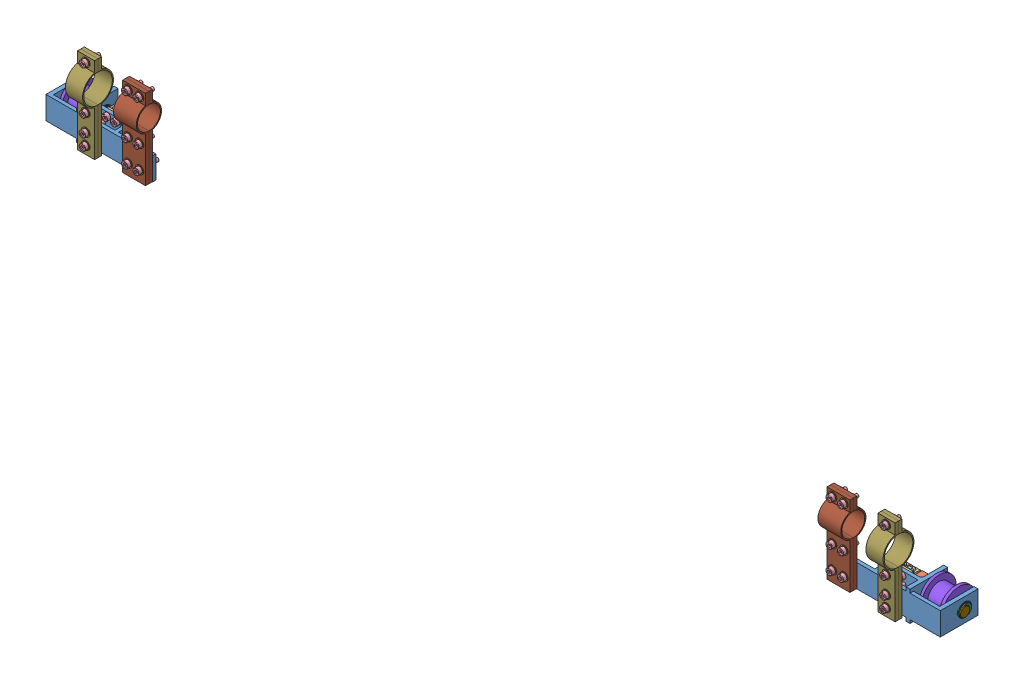
SolidWorks assembly 电机滑轮-安装, configuration 默认. Lengths in mm.
Overall size (785.6 77.7 53).
106 component instances, 12 part files, 64 mates.
Components (placement in the parent):
- 电机安装架-1: 电机安装架 [默认] at (54.9496 2.6319 18.5) size (93 26 33)
- 马达-1: 马达 [默认] at (29.2505 2.4861 -5) x (0 -1 0) z (-1 0 0) size (12 10 36)
- 电机架-1: 电机架 [默认] at (29.2505 2.4861 0) x (0 -1 0.000041) z (-1 0 0) size (25 14.79 18)
- hexagon socket head cap screws gb-2: hexagon socket head cap screws gb [GB_FASTENER_SCREWS_HSHCS M3X10-N] at (23.2502 -7.5147 14) x (0 0 -1) z (1 0 0) size (13 5.5 5.5)
- hexagon socket head cap screws gb-3: hexagon socket head cap screws gb [GB_FASTENER_SCREWS_HSHCS M3X10-N] at (15.2502 -7.5147 14) x (0 0 -1) z (1 0 0) size (13 5.5 5.5)
- hexagon socket head cap screws gb-4: hexagon socket head cap screws gb [GB_FASTENER_SCREWS_HSHCS M3X10-N] at (15.2505 12.4869 14) x (0 0 -1) z (1 0 0) size (13 5.5 5.5)
- hexagon socket head cap screws gb-5: hexagon socket head cap screws gb [GB_FASTENER_SCREWS_HSHCS M3X10-N] at (23.2505 12.4867 14) x (0 0 -1) z (1 0 0) size (13 5.5 5.5)
- hex nuts, style 1-grades ab gb-5: hex nuts, style 1-grades ab gb [GB_FASTENER_NUT_SNAB1 M3-N] at (23.2502 -7.5147 6) size (6.35 5.5 2.4)
- hex nuts, style 1-grades ab gb-7: hex nuts, style 1-grades ab gb [GB_FASTENER_NUT_SNAB1 M3-N] at (15.2502 -7.5147 6) size (6.35 5.5 2.4)
- hex nuts, style 1-grades ab gb-8: hex nuts, style 1-grades ab gb [GB_FASTENER_NUT_SNAB1 M3-N] at (23.2505 12.4867 6) size (6.35 5.5 2.4)
- hex nuts, style 1-grades ab gb-9: hex nuts, style 1-grades ab gb [GB_FASTENER_NUT_SNAB1 M3-N] at (15.2505 12.4869 6) size (6.35 5.5 2.4)
- circlips for shaft--type a small gb-2: circlips for shaft--type a small gb [GB_CONNECTING_PIECE_RING_RRA 8] at (-28.0504 2.432 -0.3255) x (0 -0.986484 0.16386) z (1 0 0) size (9.38 11.87 0.8)
- circlips for shaft--type a small gb-3: circlips for shaft--type a small gb [GB_CONNECTING_PIECE_RING_RRA 8] at (1.9496 2.5402 0.3255) x (0 -0.986484 0.16386) z (-1 0 0) size (9.38 11.87 0.8)
- plain washers-n series-grade a gb-2: plain washers-n series-grade a gb [GB_FASTENER_WASHER_PWNA 3] at (12.9496 -2.5142 28) size (7 7 0.5)
- plain washers-n series-grade a gb-3: plain washers-n series-grade a gb [GB_FASTENER_WASHER_PWNA 3] at (12.9496 7.4858 28) size (7 7 0.5)
- plain washers-n series-grade a gb-4: plain washers-n series-grade a gb [GB_FASTENER_WASHER_PWNA 3] at (59.9496 2.4861 28) size (7 7 0.5)
- plain washers-n series-grade a gb-5: plain washers-n series-grade a gb [GB_FASTENER_WASHER_PWNA 3] at (49.9496 2.4861 28) size (7 7 0.5)
- hexagon socket head cap screws gb-7: hexagon socket head cap screws gb [GB_FASTENER_SCREWS_HSHCS M3X16-N] at (12.9496 -2.5142 31) x (0 0 -1) z (1 0 0) size (19 5.5 5.5)
- hexagon socket head cap screws gb-8: hexagon socket head cap screws gb [GB_FASTENER_SCREWS_HSHCS M3X16-N] at (12.9496 7.4858 31) x (0 0 -1) z (1 0 0) size (19 5.5 5.5)
- hexagon socket head cap screws gb-9: hexagon socket head cap screws gb [GB_FASTENER_SCREWS_HSHCS M3X16-N] at (49.9496 2.4861 31) x (0 0 -1) z (0.99739 -0.072207 0) size (19 5.5 5.5)
- hexagon socket head cap screws gb-10: hexagon socket head cap screws gb [GB_FASTENER_SCREWS_HSHCS M3X16-N] at (59.9496 2.4861 31) x (0 0 -1) z (1 0 0) size (19 5.5 5.5)
- hex nuts, style 1-grades ab gb-11: hex nuts, style 1-grades ab gb [GB_FASTENER_NUT_SNAB1 M3-N] at (59.9496 2.4861 16.1) x (0.923728 0.383049 0) z (0 0 -1) size (6.35 5.5 2.4)
- hex nuts, style 1-grades ab gb-12: hex nuts, style 1-grades ab gb [GB_FASTENER_NUT_SNAB1 M3-N] at (49.9496 2.4861 16.1) x (0.923728 0.383049 0) z (0 0 -1) size (6.35 5.5 2.4)
- hex nuts, style 1-grades ab gb-13: hex nuts, style 1-grades ab gb [GB_FASTENER_NUT_SNAB1 M3-N] at (12.9496 -2.5142 16.1) x (0.923728 0.383049 0) z (0 0 -1) size (6.35 5.5 2.4)
- hex nuts, style 1-grades ab gb-14: hex nuts, style 1-grades ab gb [GB_FASTENER_NUT_SNAB1 M3-N] at (12.9496 7.4858 16.1) x (0.923728 0.383049 0) z (0 0 -1) size (6.35 5.5 2.4)
- 滑轮 - 卷帘-1: 滑轮 - 卷帘 [默认] at (-23.0504 2.4861 0) x (0 0 1) z (0 1 0) size (30 20 30)
- 滑轮轴 - 电机-1: 滑轮轴 - 电机 [默认] at (-13.0504 2.4861 0) x (0 0 -1) z (-1 0 0) size (9.5 9.5 33.6)
- deep groove ball bearings gb-1: deep groove ball bearings gb [Rolling bearings 617-8 GB 276-94] at (0.6996 2.4861 0) size (2.5 12 12)
- deep groove ball bearings gb-2: deep groove ball bearings gb [Rolling bearings 617-8 GB 276-94] at (-26.8004 2.4861 0) size (2.5 12 12)
- 小管夹具-1: 小管夹具 [默认] at (54.9496 11.6833 -31.115) x (0 0 1) z (-1 0 0) size (22 70 20)
  - 夹具-1: 夹具 [默认] at (55.615 31.0944 -10) size (11 70 20)
  - 夹具-2: 夹具 [默认] at (55.615 31.0944 10) x (-1 0 0) z (0 0 -1) size (11 70 20)
  - plain washers-n series-grade a gb-2: plain washers-n series-grade a gb [GB_FASTENER_WASHER_PWNA 3] at (59.115 46.3859 5) x (0 0 -1) z (1 0 0) size (7 7 0.5)
  - plain washers-n series-grade a gb-3: plain washers-n series-grade a gb [GB_FASTENER_WASHER_PWNA 3] at (59.115 46.3859 -5) x (0 0 -1) z (1 0 0) size (7 7 0.5)
  - plain washers-n series-grade a gb-4: plain washers-n series-grade a gb [GB_FASTENER_WASHER_PWNA 3] at (59.115 10.8029 -5) x (0 0 -1) z (1 0 0) size (7 7 0.5)
  - plain washers-n series-grade a gb-5: plain washers-n series-grade a gb [GB_FASTENER_WASHER_PWNA 3] at (59.115 10.8029 5) x (0 0 -1) z (1 0 0) size (7 7 0.5)
  - hexagon socket head cap screws gb-2: hexagon socket head cap screws gb [GB_FASTENER_SCREWS_HSHCS M3X12-N] at (62.115 10.8029 -5) x (-1 0 0) z (0 0.924225 0.381849) size (15 5.5 5.5)
  - hexagon socket head cap screws gb-3: hexagon socket head cap screws gb [GB_FASTENER_SCREWS_HSHCS M3X12-N] at (62.115 10.8029 5) x (-1 0 0) z (0 0.924225 0.381849) size (15 5.5 5.5)
  - hexagon socket head cap screws gb-4: hexagon socket head cap screws gb [GB_FASTENER_SCREWS_HSHCS M3X12-N] at (62.115 46.3859 -5) x (-1 0 0) z (0 0.924225 0.381849) size (15 5.5 5.5)
  - hexagon socket head cap screws gb-5: hexagon socket head cap screws gb [GB_FASTENER_SCREWS_HSHCS M3X12-N] at (62.115 46.3859 5) x (-1 0 0) z (0 0.924225 0.381849) size (15 5.5 5.5)
  - hex nuts, style 1-grades ab gb-2: hex nuts, style 1-grades ab gb [GB_FASTENER_NUT_SNAB1 M3-N] at (50.215 10.8029 -5) x (0 0 1) z (-1 0 0) size (6.35 5.5 2.4)
  - hex nuts, style 1-grades ab gb-3: hex nuts, style 1-grades ab gb [GB_FASTENER_NUT_SNAB1 M3-N] at (50.215 10.8029 5) x (0 0 1) z (-1 0 0) size (6.35 5.5 2.4)
  - hex nuts, style 1-grades ab gb-4: hex nuts, style 1-grades ab gb [GB_FASTENER_NUT_SNAB1 M3-N] at (50.215 46.3859 -5) x (0 0 1) z (-1 0 0) size (6.35 5.5 2.4)
  - hex nuts, style 1-grades ab gb-5: hex nuts, style 1-grades ab gb [GB_FASTENER_NUT_SNAB1 M3-N] at (50.215 46.3859 5) x (0 0 1) z (-1 0 0) size (6.35 5.5 2.4)
- 大管夹具-1: 大管夹具 [默认] at (12.9496 31.5245 -4.6251) x (0 0 1) z (-1 0 0) size (27 74.91 15)
  - 窄夹具-1: 窄夹具 [默认] at (29.1251 11.2528 -7.5) size (13.5 74.91 15)
  - 窄夹具-2: 窄夹具 [默认] at (29.1251 11.2528 7.5) x (-1 0 0) z (0 0 -1) size (13.5 74.91 15)
  - plain washers-n series-grade a gb-2: plain washers-n series-grade a gb [GB_FASTENER_WASHER_PWNA 3] at (32.6251 28.9495 0) x (0 0 -1) z (1 0 0) size (7 7 0.5)
  - plain washers-n series-grade a gb-3: plain washers-n series-grade a gb [GB_FASTENER_WASHER_PWNA 3] at (32.6251 -9.0387 0) x (0 0 -1) z (1 0 0) size (7 7 0.5)
  - hexagon socket head cap screws gb-2: hexagon socket head cap screws gb [GB_FASTENER_SCREWS_HSHCS M3X12-N] at (35.6251 -9.0387 0) x (-1 0 0) z (0 0.924225 0.381849) size (15 5.5 5.5)
  - hexagon socket head cap screws gb-3: hexagon socket head cap screws gb [GB_FASTENER_SCREWS_HSHCS M3X12-N] at (35.6251 28.9495 0) x (-1 0 0) z (0 0.924225 0.381849) size (15 5.5 5.5)
  - hex nuts, style 1-grades ab gb-2: hex nuts, style 1-grades ab gb [GB_FASTENER_NUT_SNAB1 M3-N] at (23.7251 28.9495 0) x (0 0 1) z (-1 0 0) size (6.35 5.5 2.4)
  - hex nuts, style 1-grades ab gb-3: hex nuts, style 1-grades ab gb [GB_FASTENER_NUT_SNAB1 M3-N] at (23.7251 -9.0387 0) x (0 0 1) z (-1 0 0) size (6.35 5.5 2.4)
- hexagon socket head cap screws gb-11: hexagon socket head cap screws gb [GB_FASTENER_SCREWS_HSHCS M3X16-N] at (665.9496 2.4861 31) x (0 0 -1) z (1 0 0) size (19 5.5 5.5)
- hex nuts, style 1-grades ab gb-15: hex nuts, style 1-grades ab gb [GB_FASTENER_NUT_SNAB1 M3-N] at (665.9496 2.4861 18.5) x (-0.923728 0.383049 0) z (0 0 1) size (6.35 5.5 2.4)
- hex nuts, style 1-grades ab gb-16: hex nuts, style 1-grades ab gb [GB_FASTENER_NUT_SNAB1 M3-N] at (675.9496 2.4861 18.5) x (-0.923728 0.383049 0) z (0 0 1) size (6.35 5.5 2.4)
- hex nuts, style 1-grades ab gb-17: hex nuts, style 1-grades ab gb [GB_FASTENER_NUT_SNAB1 M3-N] at (712.9496 -2.5142 18.5) x (-0.923728 0.383049 0) z (0 0 1) size (6.35 5.5 2.4)
- hex nuts, style 1-grades ab gb-18: hex nuts, style 1-grades ab gb [GB_FASTENER_NUT_SNAB1 M3-N] at (712.9496 7.4858 18.5) x (-0.923728 0.383049 0) z (0 0 1) size (6.35 5.5 2.4)
- 滑轮 - 卷帘-2: 滑轮 - 卷帘 [默认] at (728.9496 2.4861 0) x (0 0 1) z (0 1 0) size (30 20 30)
- 滑轮轴 - 电机-2: 滑轮轴 - 电机 [默认] at (738.9496 2.4861 1.5) x (0 0 1) z (1 0 0) size (9.5 9.5 33.6)
- deep groove ball bearings gb-3: deep groove ball bearings gb [Rolling bearings 617-8 GB 276-94] at (725.1996 2.4861 0) x (-1 0 0) z (0 0 -1) size (2.5 12 12)
- deep groove ball bearings gb-4: deep groove ball bearings gb [Rolling bearings 617-8 GB 276-94] at (752.6996 2.4861 0) x (-1 0 0) z (0 0 -1) size (2.5 12 12)
- 小管夹具-2: 小管夹具 [默认] at (670.9496 11.6833 -31.115) x (0 0 1) z (-1 0 0) size (22 70 20)
  - 夹具-1: 夹具 [默认] at (55.615 31.0944 -10) size (11 70 20)
  - 夹具-2: 夹具 [默认] at (55.615 31.0944 10) x (-1 0 0) z (0 0 -1) size (11 70 20)
  - plain washers-n series-grade a gb-2: plain washers-n series-grade a gb [GB_FASTENER_WASHER_PWNA 3] at (59.115 46.3859 5) x (0 0 -1) z (1 0 0) size (7 7 0.5)
  - plain washers-n series-grade a gb-3: plain washers-n series-grade a gb [GB_FASTENER_WASHER_PWNA 3] at (59.115 46.3859 -5) x (0 0 -1) z (1 0 0) size (7 7 0.5)
  - plain washers-n series-grade a gb-4: plain washers-n series-grade a gb [GB_FASTENER_WASHER_PWNA 3] at (59.115 10.8029 -5) x (0 0 -1) z (1 0 0) size (7 7 0.5)
  - plain washers-n series-grade a gb-5: plain washers-n series-grade a gb [GB_FASTENER_WASHER_PWNA 3] at (59.115 10.8029 5) x (0 0 -1) z (1 0 0) size (7 7 0.5)
  - hexagon socket head cap screws gb-2: hexagon socket head cap screws gb [GB_FASTENER_SCREWS_HSHCS M3X12-N] at (62.115 10.8029 -5) x (-1 0 0) z (0 0.924225 0.381849) size (15 5.5 5.5)
  - hexagon socket head cap screws gb-3: hexagon socket head cap screws gb [GB_FASTENER_SCREWS_HSHCS M3X12-N] at (62.115 10.8029 5) x (-1 0 0) z (0 0.924225 0.381849) size (15 5.5 5.5)
  - hexagon socket head cap screws gb-4: hexagon socket head cap screws gb [GB_FASTENER_SCREWS_HSHCS M3X12-N] at (62.115 46.3859 -5) x (-1 0 0) z (0 0.924225 0.381849) size (15 5.5 5.5)
  - hexagon socket head cap screws gb-5: hexagon socket head cap screws gb [GB_FASTENER_SCREWS_HSHCS M3X12-N] at (62.115 46.3859 5) x (-1 0 0) z (0 0.924225 0.381849) size (15 5.5 5.5)
  - hex nuts, style 1-grades ab gb-2: hex nuts, style 1-grades ab gb [GB_FASTENER_NUT_SNAB1 M3-N] at (50.215 10.8029 -5) x (0 0 1) z (-1 0 0) size (6.35 5.5 2.4)
  - hex nuts, style 1-grades ab gb-3: hex nuts, style 1-grades ab gb [GB_FASTENER_NUT_SNAB1 M3-N] at (50.215 10.8029 5) x (0 0 1) z (-1 0 0) size (6.35 5.5 2.4)
  - hex nuts, style 1-grades ab gb-4: hex nuts, style 1-grades ab gb [GB_FASTENER_NUT_SNAB1 M3-N] at (50.215 46.3859 -5) x (0 0 1) z (-1 0 0) size (6.35 5.5 2.4)
  - hex nuts, style 1-grades ab gb-5: hex nuts, style 1-grades ab gb [GB_FASTENER_NUT_SNAB1 M3-N] at (50.215 46.3859 5) x (0 0 1) z (-1 0 0) size (6.35 5.5 2.4)
- 大管夹具-2: 大管夹具 [默认] at (712.9496 31.5245 -4.6251) x (0 0 1) z (-1 0 0) size (27 74.91 15)
  - 窄夹具-1: 窄夹具 [默认] at (29.1251 11.2528 -7.5) size (13.5 74.91 15)
  - 窄夹具-2: 窄夹具 [默认] at (29.1251 11.2528 7.5) x (-1 0 0) z (0 0 -1) size (13.5 74.91 15)
  - plain washers-n series-grade a gb-2: plain washers-n series-grade a gb [GB_FASTENER_WASHER_PWNA 3] at (32.6251 28.9495 0) x (0 0 -1) z (1 0 0) size (7 7 0.5)
  - plain washers-n series-grade a gb-3: plain washers-n series-grade a gb [GB_FASTENER_WASHER_PWNA 3] at (32.6251 -9.0387 0) x (0 0 -1) z (1 0 0) size (7 7 0.5)
  - hexagon socket head cap screws gb-2: hexagon socket head cap screws gb [GB_FASTENER_SCREWS_HSHCS M3X12-N] at (35.6251 -9.0387 0) x (-1 0 0) z (0 0.924225 0.381849) size (15 5.5 5.5)
  - hexagon socket head cap screws gb-3: hexagon socket head cap screws gb [GB_FASTENER_SCREWS_HSHCS M3X12-N] at (35.6251 28.9495 0) x (-1 0 0) z (0 0.924225 0.381849) size (15 5.5 5.5)
  - hex nuts, style 1-grades ab gb-2: hex nuts, style 1-grades ab gb [GB_FASTENER_NUT_SNAB1 M3-N] at (23.7251 28.9495 0) x (0 0 1) z (-1 0 0) size (6.35 5.5 2.4)
  - hex nuts, style 1-grades ab gb-3: hex nuts, style 1-grades ab gb [GB_FASTENER_NUT_SNAB1 M3-N] at (23.7251 -9.0387 0) x (0 0 1) z (-1 0 0) size (6.35 5.5 2.4)
- hex nuts, style 1-grades ab gb-19: hex nuts, style 1-grades ab gb [GB_FASTENER_NUT_SNAB1 M3-N] at (710.649 -7.5147 3.6) x (-1 0 0) z (0 0 -1) size (6.35 5.5 2.4)
- hexagon socket head cap screws gb-12: hexagon socket head cap screws gb [GB_FASTENER_SCREWS_HSHCS M3X10-N] at (702.649 -7.5147 14) x (0 0 -1) z (1 0 0) size (13 5.5 5.5)
- hex nuts, style 1-grades ab gb-20: hex nuts, style 1-grades ab gb [GB_FASTENER_NUT_SNAB1 M3-N] at (702.6488 12.4867 3.6) x (-1 0 0) z (0 0 -1) size (6.35 5.5 2.4)
- 电机架-2: 电机架 [默认] at (696.6488 2.4861 0) x (0 1 -0.000041) z (1 0 0) size (25 14.79 18)
- hexagon socket head cap screws gb-13: hexagon socket head cap screws gb [GB_FASTENER_SCREWS_HSHCS M3X10-N] at (702.6488 12.4867 14) x (0 0 -1) z (1 0 0) size (13 5.5 5.5)
- hex nuts, style 1-grades ab gb-21: hex nuts, style 1-grades ab gb [GB_FASTENER_NUT_SNAB1 M3-N] at (702.649 -7.5147 3.6) x (-1 0 0) z (0 0 -1) size (6.35 5.5 2.4)
- hexagon socket head cap screws gb-14: hexagon socket head cap screws gb [GB_FASTENER_SCREWS_HSHCS M3X10-N] at (710.649 -7.5147 14) x (0 0 -1) z (1 0 0) size (13 5.5 5.5)
- hexagon socket head cap screws gb-15: hexagon socket head cap screws gb [GB_FASTENER_SCREWS_HSHCS M3X10-N] at (710.6488 12.4869 14) x (0 0 -1) z (1 0 0) size (13 5.5 5.5)
- plain washers-n series-grade a gb-6: plain washers-n series-grade a gb [GB_FASTENER_WASHER_PWNA 3] at (675.9496 2.4861 27.5) x (-1 0 0) z (0 0 -1) size (7 7 0.5)
- circlips for shaft--type a small gb-4: circlips for shaft--type a small gb [GB_CONNECTING_PIECE_RING_RRA 8] at (723.1496 2.5402 0.3255) x (0 -0.986484 0.16386) z (-1 0 0) size (9.38 11.87 0.8)
- plain washers-n series-grade a gb-7: plain washers-n series-grade a gb [GB_FASTENER_WASHER_PWNA 3] at (712.9496 -2.5142 27.5) x (-1 0 0) z (0 0 -1) size (7 7 0.5)
- plain washers-n series-grade a gb-8: plain washers-n series-grade a gb [GB_FASTENER_WASHER_PWNA 3] at (712.9496 7.4858 27.5) x (-1 0 0) z (0 0 -1) size (7 7 0.5)
- hex nuts, style 1-grades ab gb-22: hex nuts, style 1-grades ab gb [GB_FASTENER_NUT_SNAB1 M3-N] at (710.6488 12.4869 3.6) x (-1 0 0) z (0 0 -1) size (6.35 5.5 2.4)
- circlips for shaft--type a small gb-5: circlips for shaft--type a small gb [GB_CONNECTING_PIECE_RING_RRA 8] at (754.7496 2.432 -0.3255) x (0 -0.986484 0.16386) z (1 0 0) size (9.38 11.87 0.8)
- plain washers-n series-grade a gb-9: plain washers-n series-grade a gb [GB_FASTENER_WASHER_PWNA 3] at (665.9496 2.4861 27.5) x (-1 0 0) z (0 0 -1) size (7 7 0.5)
- hexagon socket head cap screws gb-16: hexagon socket head cap screws gb [GB_FASTENER_SCREWS_HSHCS M3X16-N] at (675.9496 2.4861 31) x (0 0 -1) z (0.99739 0.072207 0) size (19 5.5 5.5)
- hexagon socket head cap screws gb-17: hexagon socket head cap screws gb [GB_FASTENER_SCREWS_HSHCS M3X16-N] at (712.9496 7.4858 31) x (0 0 -1) z (1 0 0) size (19 5.5 5.5)
- hexagon socket head cap screws gb-18: hexagon socket head cap screws gb [GB_FASTENER_SCREWS_HSHCS M3X16-N] at (712.9496 -2.5142 31) x (0 0 -1) z (1 0 0) size (19 5.5 5.5)
- 电机安装架-2: 电机安装架 [默认] at (670.9496 2.3404 18.5) x (-1 0 0) z (0 0 1) size (93 26 33)
- 马达-2: 马达 [默认] at (696.6488 2.4861 -5) x (0 1 0) z (1 0 0) size (12 10 36)
Mates (geometry in assembly coordinates):
- 同心1: concentric aligned: cylinder of 马达-1 through (14.2505 2.4861 0) axis (1 0 0) radius 6; cylinder of 电机架-1 through (14.2505 2.4861 0) axis (1 0 0) radius 6
- 重合1: coincident anti-aligned: plane of 马达-1 through (14.2505 5.8027 5) normal (0 0 1); plane of 电机架-1 through (14.2505 2.4861 5) normal (0 0 -1)
- 重合2: coincident anti-aligned: plane of 马达-1 through (14.2505 2.4861 -5) normal (1 0 0); plane of 电机架-1 through (14.2505 2.4861 0) normal (-1 0 0)
- 同心4: concentric anti-aligned: cylinder of 电机安装架-1 through (9.9496 2.4861 0) axis (-1 0 0) radius 6; cylinder of 马达-1 through (-5.7495 2.4861 0) axis (1 0 0) radius 1.5
- 同心5: concentric aligned: cylinder of 电机安装架-1 through (23.2502 -7.5147 1) axis (0 0 1) radius 1.5; cylinder of 电机架-1 through (23.2502 -7.5147 -2.0002) axis (0 0 1) radius 1.5
- 同心6: concentric aligned: cylinder of 电机安装架-1 through (23.2502 -7.5147 1) axis (0 0 1) radius 1.5; cylinder of hexagon socket head cap screws gb-2 through (23.2502 -7.5147 1) axis (0 0 1) radius 1.5
- 重合5: coincident anti-aligned: plane of 电机安装架-1 through (32.2496 -10.5139 11) normal (0 0 1); plane of hexagon socket head cap screws gb-2 through (23.2502 -7.5147 11) normal (0 0 -1)
- 同心7: concentric aligned: cylinder of 电机安装架-1 through (15.2502 -7.5147 1) axis (0 0 1) radius 1.5; cylinder of hexagon socket head cap screws gb-3 through (15.2502 -7.5147 1) axis (0 0 1) radius 1.5
- 重合6: coincident anti-aligned: plane of 电机安装架-1 through (32.2496 -10.5139 11) normal (0 0 1); plane of hexagon socket head cap screws gb-3 through (15.2502 -7.5147 11) normal (0 0 -1)
- 同心8: concentric aligned: cylinder of 电机安装架-1 through (15.2505 12.4869 1) axis (0 0 1) radius 1.5; cylinder of hexagon socket head cap screws gb-4 through (15.2505 12.4869 1) axis (0 0 1) radius 1.5
- 重合7: coincident anti-aligned: plane of 电机安装架-1 through (32.2496 -10.5139 11) normal (0 0 1); plane of hexagon socket head cap screws gb-4 through (15.2505 12.4869 11) normal (0 0 -1)
- 同心9: concentric aligned: cylinder of 电机安装架-1 through (23.2505 12.4867 1) axis (0 0 1) radius 1.5; cylinder of hexagon socket head cap screws gb-5 through (23.2505 12.4867 1) axis (0 0 1) radius 1.5
- 重合8: coincident anti-aligned: plane of 电机安装架-1 through (32.2496 -10.5139 11) normal (0 0 1); plane of hexagon socket head cap screws gb-5 through (23.2505 12.4867 11) normal (0 0 -1)
- 同心12: concentric aligned: cylinder of hexagon socket head cap screws gb-2 through (23.2502 -7.5147 1) axis (0 0 1) radius 1.5; cylinder of hex nuts, style 1-grades ab gb-5 through (23.2502 -7.5147 3.6) axis (0 0 1) radius 1.2295
- 距离21: distance = 2 mm anti-aligned: plane of 电机安装架-1 through (32.2496 15.4861 8) normal (0 0 -1); plane of hex nuts, style 1-grades ab gb-5 through (23.2502 -13.0147 6) normal (0 0 1)
- 同心13: concentric aligned: cylinder of hexagon socket head cap screws gb-3 through (15.2502 -7.5147 1) axis (0 0 1) radius 1.5; cylinder of hex nuts, style 1-grades ab gb-7 through (15.2502 -7.5147 3.6) axis (0 0 1) radius 1.2295
- 同心14: concentric aligned: cylinder of hexagon socket head cap screws gb-5 through (23.2505 12.4867 1) axis (0 0 1) radius 1.5; cylinder of hex nuts, style 1-grades ab gb-8 through (23.2505 12.4867 3.6) axis (0 0 1) radius 1.2295
- 同心15: concentric aligned: cylinder of hexagon socket head cap screws gb-4 through (15.2505 12.4869 1) axis (0 0 1) radius 1.5; cylinder of hex nuts, style 1-grades ab gb-9 through (15.2505 12.4869 3.6) axis (0 0 1) radius 1.2295
- 距离31: distance = 2 mm anti-aligned: plane of hex nuts, style 1-grades ab gb-8 through (23.2505 6.9867 6) normal (0 0 1); plane of 电机安装架-1 through (32.2496 15.4861 8) normal (0 0 -1)
- 距离41: distance = 5 mm aligned: plane of hex nuts, style 1-grades ab gb-9 through (15.2505 6.9869 6) normal (0 0 1); plane of 电机安装架-1 through (32.2496 -10.5139 11) normal (0 0 1)
- 距离51: distance = 5 mm aligned: plane of hex nuts, style 1-grades ab gb-7 through (15.2502 -13.0147 6) normal (0 0 1); plane of 电机安装架-1 through (32.2496 -10.5139 11) normal (0 0 1)
- 同心161: concentric anti-aligned: cylinder of 滑轮 - 卷帘-1 through (-3.0504 2.4861 0) axis (-1 0 0) radius 4; cylinder of 滑轮轴 - 电机-1 through (-29.8504 2.4861 0) axis (1 0 0) radius 4
- 重合231: coincident anti-aligned: plane of 滑轮 - 卷帘-1 through (-3.0504 2.4861 1.53) normal (0 0 -1); plane of 滑轮轴 - 电机-1 through (-23.0504 6.1819 1.53) normal (0 0 1)
- 重合241: coincident aligned: plane of 滑轮 - 卷帘-1 through (-3.0504 2.4861 0) normal (1 0 0); plane of 滑轮轴 - 电机-1 through (-3.0504 2.4861 0) normal (1 0 0)
- 同心171: concentric aligned: cylinder of 电机安装架-1 through (9.9496 2.4861 0) axis (-1 0 0) radius 6; cylinder of deep groove ball bearings gb-1 through (-6.2718 2.4861 0) axis (-1 0 0) radius 4
- 重合251: coincident anti-aligned: plane of 电机安装架-1 through (-0.5504 2.4861 0) normal (1 0 0); plane of deep groove ball bearings gb-1 through (-0.5504 8.4861 0) normal (-1 0 0)
- 同心181: concentric aligned: cylinder of 电机安装架-1 through (9.9496 2.4861 0) axis (-1 0 0) radius 6; cylinder of deep groove ball bearings gb-2 through (-33.7718 2.4861 0) axis (-1 0 0) radius 4
- 重合261: coincident anti-aligned: plane of 电机安装架-1 through (-25.5504 2.4861 0) normal (-1 0 0); plane of deep groove ball bearings gb-2 through (-25.5504 8.4861 0) normal (1 0 0)
- 同心19: concentric aligned: cylinder of 滑轮轴 - 电机-1 through (5.7496 2.4861 0) axis (1 0 0) radius 3.7; cylinder of circlips for shaft--type a small gb-2 through (-28.8504 2.4861 0) axis (1 0 0) radius 3.7
- 重合27: coincident anti-aligned: plane of 滑轮轴 - 电机-1 through (-28.0504 -1.5139 0) normal (-1 0 0); plane of circlips for shaft--type a small gb-2 through (-28.0504 3.9384 5.0817) normal (1 0 0)
- 同心20: concentric anti-aligned: cylinder of 滑轮轴 - 电机-1 through (-29.8504 2.4861 0) axis (1 0 0) radius 4; cylinder of circlips for shaft--type a small gb-3 through (2.7496 2.4861 0) axis (-1 0 0) radius 3.7
- 重合28: coincident anti-aligned: plane of 滑轮轴 - 电机-1 through (1.9496 -1.5139 0) normal (1 0 0); plane of circlips for shaft--type a small gb-3 through (1.9496 2.2176 -5.2784) normal (-1 0 0)
- 同心221: concentric aligned: cylinder of 马达-1 through (-5.7495 2.4861 0) axis (1 0 0) radius 1.5; cylinder of 滑轮轴 - 电机-1 through (-16.2504 2.4861 0) axis (1 0 0) radius 1.5
- 重合31: coincident anti-aligned: plane of deep groove ball bearings gb-2 through (-28.0504 7.1528 0) normal (-1 0 0); plane of circlips for shaft--type a small gb-2 through (-28.0504 3.9384 5.0817) normal (1 0 0)
- 同心222: concentric anti-aligned: cylinder of 电机安装架-1 through (12.9496 7.4858 16.5) axis (0 0 1) radius 1.5; cylinder of 大管夹具-1/窄夹具-1 through (12.9496 7.4858 41.5) axis (0 0 -1) radius 1.5
- 重合262: coincident anti-aligned: plane of 电机安装架-1 through (54.9496 2.6319 21.5) normal (0 0 1); plane of 大管夹具-1/窄夹具-1 through (5.4496 42.7773 21.5) normal (0 0 -1)
- 同心223: concentric aligned: cylinder of 电机安装架-1 through (12.9496 -2.5142 16.5) axis (0 0 1) radius 1.5; cylinder of 大管夹具-1/窄夹具-2 through (12.9496 -2.5142 7.5) axis (0 0 1) radius 1.5
- 同心224: concentric anti-aligned: cylinder of 电机安装架-1 through (59.9496 2.4861 21.5) axis (0 0 -1) radius 1.5; cylinder of 小管夹具-1/夹具-2 through (59.9496 2.4861 7.5) axis (0 0 1) radius 1.5
- 同心225: concentric aligned: cylinder of 电机安装架-1 through (49.9496 2.4861 21.5) axis (0 0 -1) radius 1.5; cylinder of 小管夹具-1/夹具-1 through (49.9496 2.4861 41.5) axis (0 0 -1) radius 1.5
- 重合263: coincident anti-aligned: plane of 电机安装架-1 through (54.9496 2.6319 21.5) normal (0 0 1); plane of 小管夹具-1/夹具-1 through (44.9496 42.7776 21.5) normal (0 0 -1)
- 同心226: concentric aligned: cylinder of 大管夹具-1/窄夹具-2 through (12.9496 -2.5142 7.5) axis (0 0 1) radius 1.5; cylinder of plain washers-n series-grade a gb-2 through (12.9496 -2.5142 27.5) axis (0 0 1) radius 1.6
- 重合264: coincident anti-aligned: plane of 大管夹具-1/窄夹具-2 through (20.4496 42.7773 27.5) normal (0 0 1); plane of plain washers-n series-grade a gb-2 through (12.9496 -2.5142 27.5) normal (0 0 -1)
- 同心227: concentric aligned: cylinder of 大管夹具-1/窄夹具-2 through (12.9496 7.4858 7.5) axis (0 0 1) radius 1.5; cylinder of plain washers-n series-grade a gb-3 through (12.9496 7.4858 27.5) axis (0 0 1) radius 1.6
- 重合265: coincident anti-aligned: plane of 大管夹具-1/窄夹具-2 through (20.4496 42.7773 27.5) normal (0 0 1); plane of plain washers-n series-grade a gb-3 through (12.9496 7.4858 27.5) normal (0 0 -1)
- 同心228: concentric aligned: cylinder of 小管夹具-1/夹具-2 through (59.9496 2.4861 7.5) axis (0 0 1) radius 1.5; cylinder of plain washers-n series-grade a gb-4 through (59.9496 2.4861 27.5) axis (0 0 1) radius 1.6
- 重合266: coincident anti-aligned: plane of 小管夹具-1/夹具-2 through (64.9496 42.7776 27.5) normal (0 0 1); plane of plain washers-n series-grade a gb-4 through (59.9496 2.4861 27.5) normal (0 0 -1)
- 同心229: concentric aligned: cylinder of 小管夹具-1/夹具-2 through (49.9496 2.4861 7.5) axis (0 0 1) radius 1.5; cylinder of plain washers-n series-grade a gb-5 through (49.9496 2.4861 27.5) axis (0 0 1) radius 1.6
- 重合267: coincident anti-aligned: plane of 小管夹具-1/夹具-2 through (64.9496 42.7776 27.5) normal (0 0 1); plane of plain washers-n series-grade a gb-5 through (49.9496 2.4861 27.5) normal (0 0 -1)
- 同心230: concentric aligned: cylinder of 大管夹具-1/窄夹具-2 through (12.9496 -2.5142 7.5) axis (0 0 1) radius 1.5; cylinder of hexagon socket head cap screws gb-7 through (12.9496 -2.5142 12) axis (0 0 1) radius 1.5
- 重合268: coincident anti-aligned: plane of plain washers-n series-grade a gb-2 through (12.9496 -2.5142 28) normal (0 0 1); plane of hexagon socket head cap screws gb-7 through (12.9496 -2.5142 28) normal (0 0 -1)
- 同心231: concentric aligned: cylinder of plain washers-n series-grade a gb-3 through (12.9496 7.4858 27.5) axis (0 0 1) radius 3.5; cylinder of hexagon socket head cap screws gb-8 through (12.9496 7.4858 12) axis (0 0 1) radius 1.5
- 重合269: coincident anti-aligned: plane of plain washers-n series-grade a gb-3 through (12.9496 7.4858 28) normal (0 0 1); plane of hexagon socket head cap screws gb-8 through (12.9496 7.4858 28) normal (0 0 -1)
- 同心232: concentric aligned: cylinder of 小管夹具-1/夹具-2 through (49.9496 2.4861 7.5) axis (0 0 1) radius 1.5; cylinder of hexagon socket head cap screws gb-9 through (49.9496 2.4861 12) axis (0 0 1) radius 1.5
- 同心233: concentric aligned: cylinder of 小管夹具-1/夹具-2 through (59.9496 2.4861 7.5) axis (0 0 1) radius 1.5; cylinder of hexagon socket head cap screws gb-10 through (59.9496 2.4861 12) axis (0 0 1) radius 1.5
- 重合271: coincident anti-aligned: plane of plain washers-n series-grade a gb-4 through (59.9496 2.4861 28) normal (0 0 1); plane of hexagon socket head cap screws gb-10 through (59.9496 2.4861 28) normal (0 0 -1)
- 重合2721: coincident anti-aligned: plane of plain washers-n series-grade a gb-5 through (49.9496 2.4861 28) normal (0 0 1); plane of hexagon socket head cap screws gb-9 through (49.9496 2.4861 28) normal (0 0 -1)
- 同心234: concentric anti-aligned: cylinder of hexagon socket head cap screws gb-10 through (59.9496 2.4861 12) axis (0 0 1) radius 1.5; cone of hex nuts, style 1-grades ab gb-11 through (59.9496 2.4861 18.5) axis (0 0 -1)
- 重合273: coincident anti-aligned: plane of 电机安装架-1 through (54.9496 2.6319 18.5) normal (0 0 -1); plane of hex nuts, style 1-grades ab gb-11 through (57.8429 7.5666 18.5) normal (0 0 1)
- 同心235: concentric anti-aligned: cylinder of hexagon socket head cap screws gb-9 through (49.9496 2.4861 12) axis (0 0 1) radius 1.5; cylinder of hex nuts, style 1-grades ab gb-12 through (49.9496 2.4861 18.5) axis (0 0 -1) radius 523.5988
- 重合274: coincident anti-aligned: plane of 电机安装架-1 through (54.9496 2.6319 18.5) normal (0 0 -1); plane of hex nuts, style 1-grades ab gb-12 through (47.8429 7.5666 18.5) normal (0 0 1)
- 同心236: concentric anti-aligned: cylinder of hexagon socket head cap screws gb-7 through (12.9496 -2.5142 12) axis (0 0 1) radius 1.5; cylinder of hex nuts, style 1-grades ab gb-13 through (12.9496 -2.5142 18.5) axis (0 0 -1) radius 523.5988
- 重合275: coincident anti-aligned: plane of 电机安装架-1 through (54.9496 2.6319 18.5) normal (0 0 -1); plane of hex nuts, style 1-grades ab gb-13 through (10.8429 2.5663 18.5) normal (0 0 1)
- 同心237: concentric anti-aligned: cylinder of 电机安装架-1 through (12.9496 7.4858 16.5) axis (0 0 1) radius 1.5; cylinder of hex nuts, style 1-grades ab gb-14 through (12.9496 7.4858 18.5) axis (0 0 -1) radius 523.5988
- 重合276: coincident anti-aligned: plane of 电机安装架-1 through (54.9496 2.6319 18.5) normal (0 0 -1); plane of hex nuts, style 1-grades ab gb-14 through (10.8429 12.5663 18.5) normal (0 0 1)
